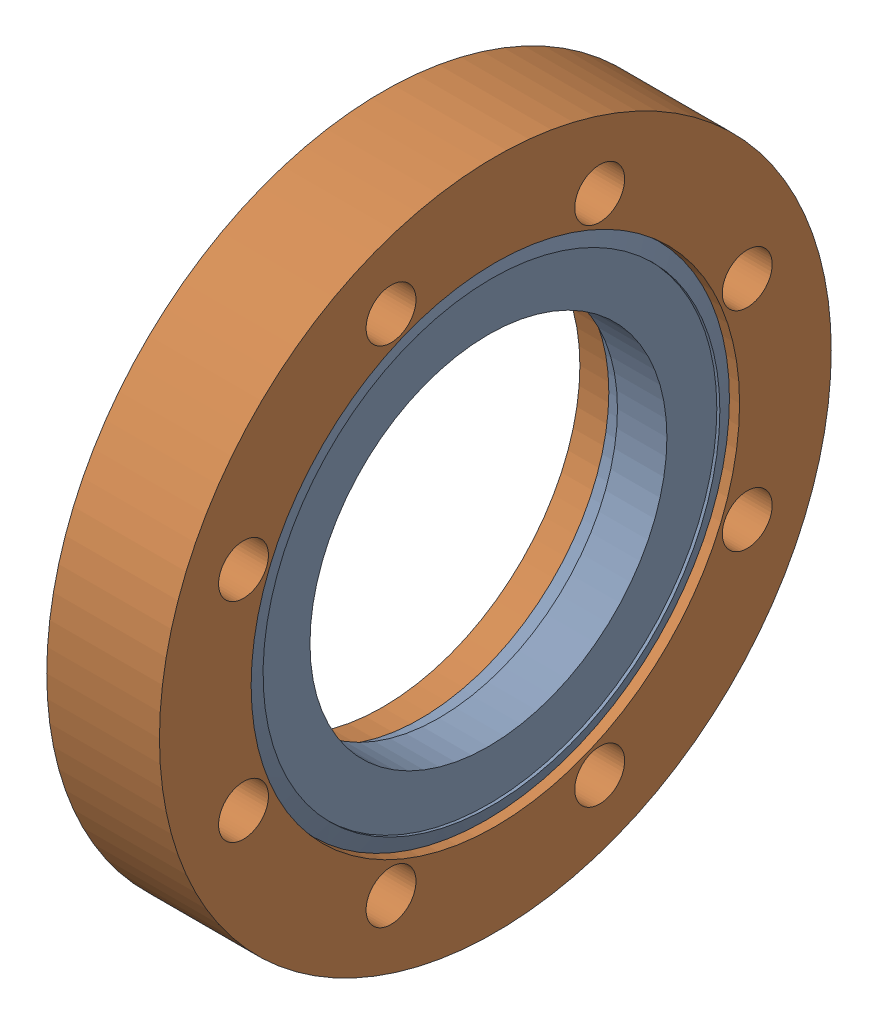
SolidWorks assembly 100021 (4.5 X 2.5 R)_2, configuration Default. Lengths in mm.
Overall size (19.05 113.54 113.54).
2 component instances, 2 part files, 0 mates.
Components (placement in the parent):
- 100021 (4.5 X 2.5 INS)_2-1: 100021 (4.5 X 2.5 INS)_2 [Default] at origin size (12.04 82.3 82.3)
- 100021 (4.5 X 2.5 REC)_2-1: 100021 (4.5 X 2.5 REC)_2 [Default] at (-6.35 0 0) x (1 0 0) z (0 0 -1) size (19.05 113.54 113.54)
